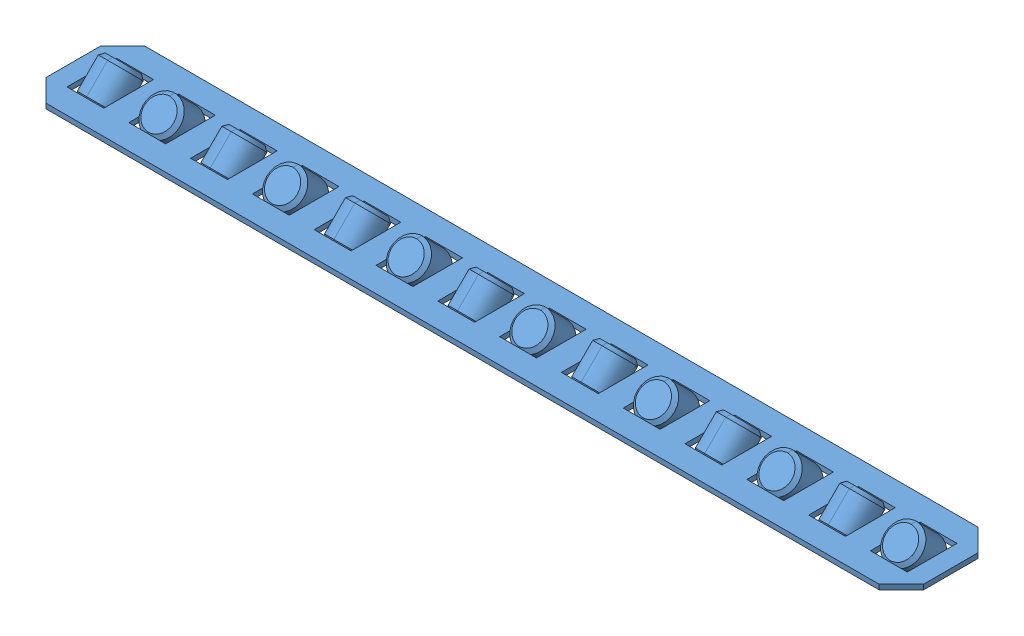
SolidWorks assembly VR3___100H_x_14Z__0_, configuration Default. Lengths in mm.
Overall size (101.57 18 8.3).
3 component instances, 3 part files, 0 mates.
Components (placement in the parent):
- _VR3_100_14Z_Roller_guide_2-1: _VR3_100_14Z_Roller_guide_2 [Default] at origin size (101.57 8.3 8.3)
- _VR3_100_14Z_Roller_cage_4-1: _VR3_100_14Z_Roller_cage_4 [Default] at (16.5 0 0) x (1 0 0) z (0 1 0) size (71 8 4.24)
- _VR3_100_14Z_Roller_guide__Top_6-1: _VR3_100_14Z_Roller_guide__Top_6 [Default] x (1 0 0) z (0 0 -1) size (101.57 8.3 8.3)
